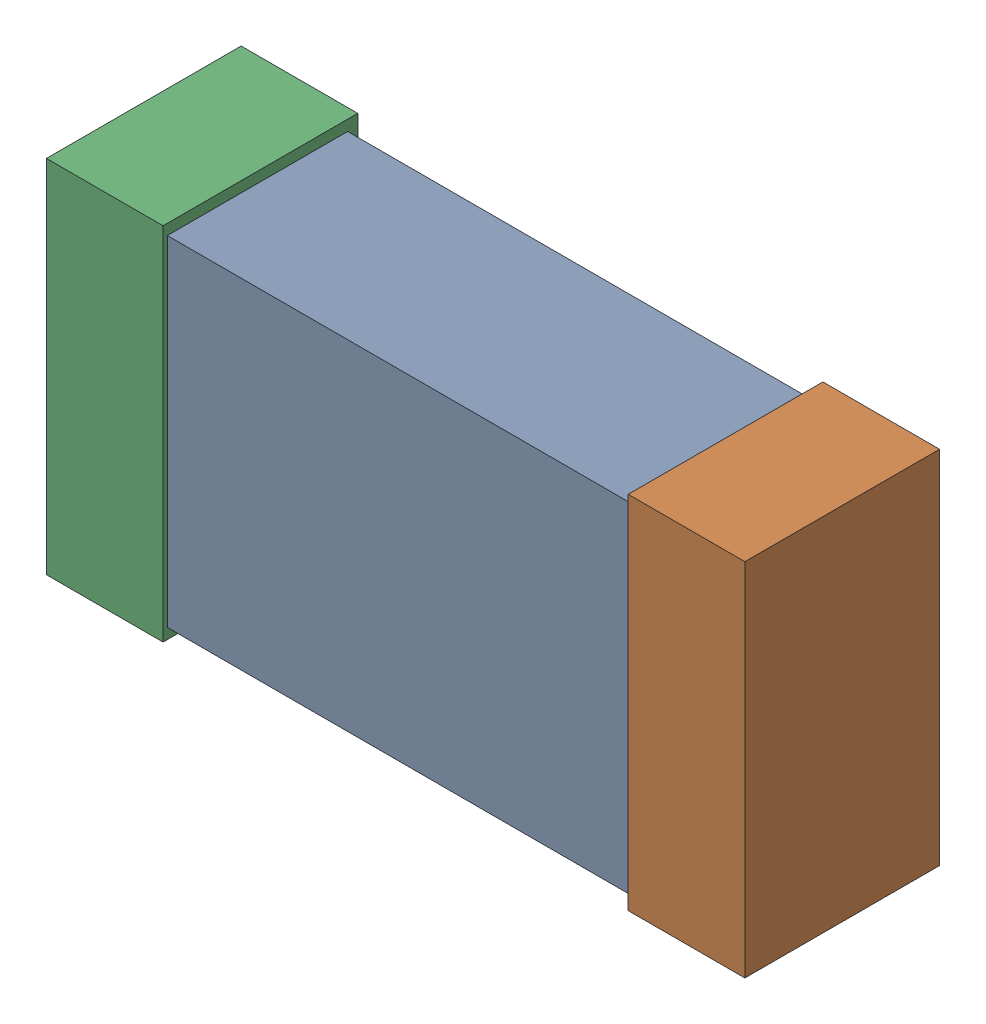
SolidWorks assembly C1, configuration Default. Lengths in mm.
Overall size (1.65 0.85 0.46).
6 component instances, 2 part files, 0 mates.
Components (placement in the parent):
- 432120720_5-1: 432120720_5 [Default] at (34.8457 18.3612 0.025) size (1.5 0.8 0.42)
  - Extruded (12)-1: Extruded (12) [Default] at origin size (1.5 0.8 0.42)
- 432120464_10-1: 432120464_10 [Default] at (35.5315 18.3612 0.001) size (0.28 0.85 0.46)
  - Extruded (11)-1: Extruded (11) [Default] at origin size (0.28 0.85 0.46)
- 432120464_11-1: 432120464_11 [Default] at (34.16 18.3612 0.001) size (0.28 0.85 0.46)
  - Extruded (11)-1: Extruded (11) [Default] at origin size (0.28 0.85 0.46)
